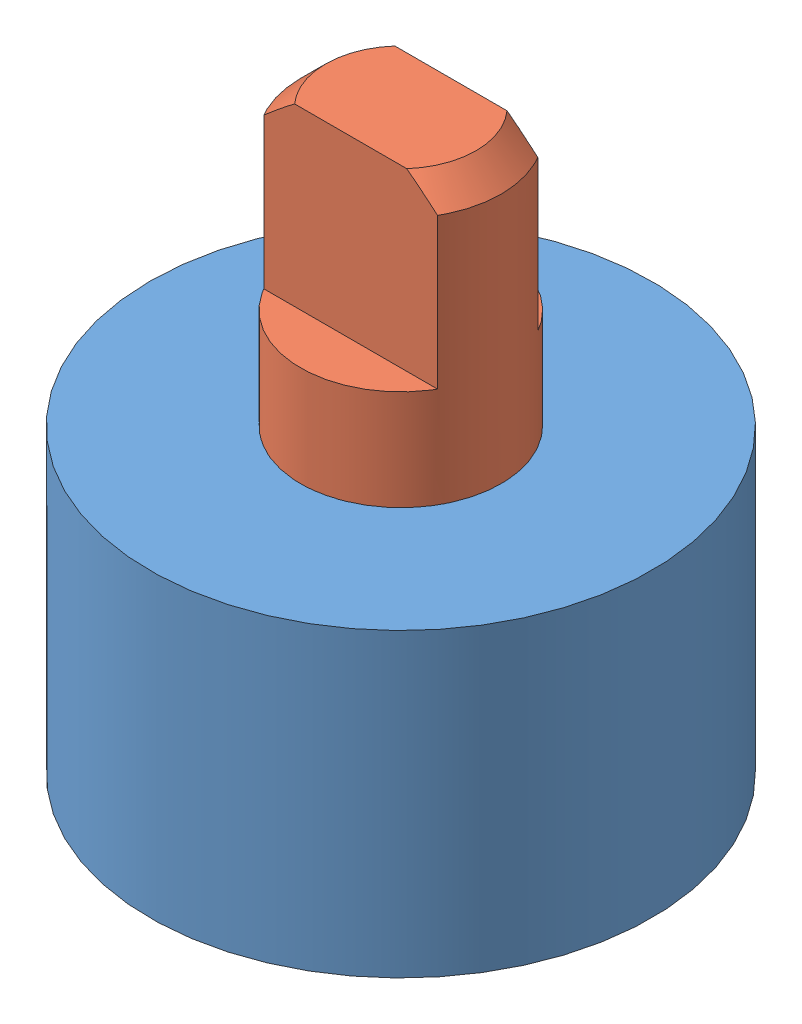
SolidWorks assembly Птнц, configuration По умолчанию. Lengths in mm.
Overall size (10 11.5 10).
2 component instances, 2 part files, 2 mates.
Components (placement in the parent):
- Птнц_корп-1: Птнц_корп [По умолчанию] at origin size (10 6 10)
- Птнц_вал-1: Птнц_вал [По умолчанию] at (0 7.75 0)
Mates (geometry in assembly coordinates):
- Совпадение1: coincident anti-aligned: plane of Птнц_корп-1 through (-2 4 0) normal (0 1 0); plane of Птнц_вал-1 through (0 4 0) normal (0 -1 0)
- Концентричный1: concentric anti-aligned: cylinder of Птнц_корп-1 through (0 4 0) axis (0 1 0) radius 2; cylinder of Птнц_вал-1 through (0 11.5 0) axis (0 -1 0) radius 2
